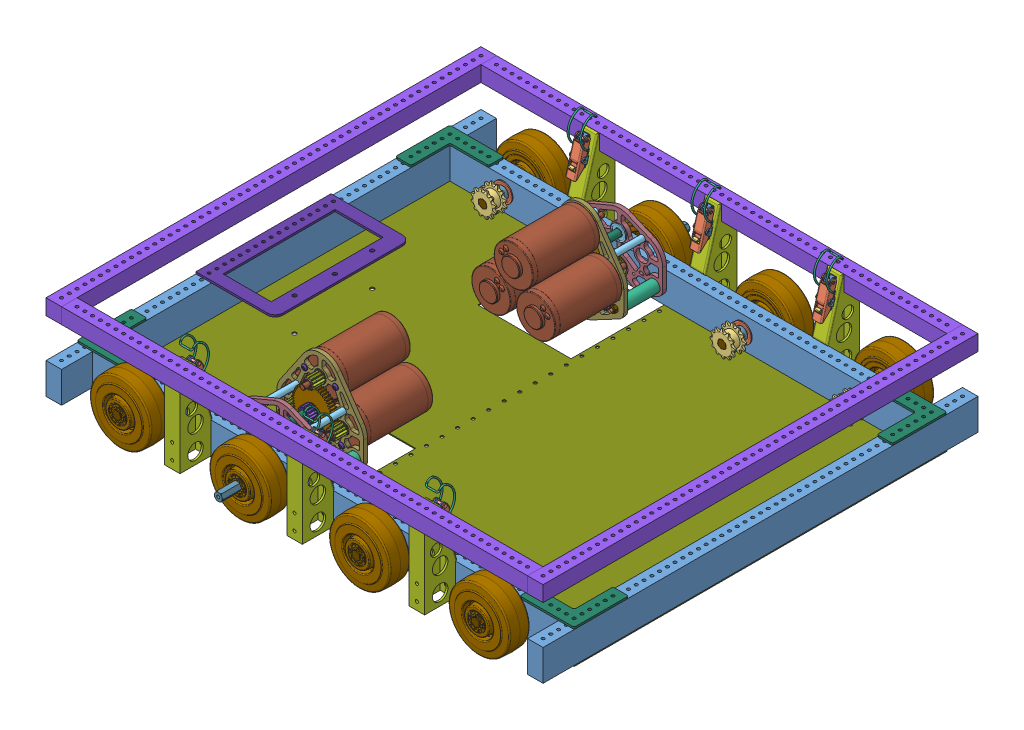
SolidWorks assembly 1991-17-DA-006, configuration Default. Lengths in mm.
Overall size (1080.45 209.9 1407.35).
201 component instances, 45 part files, 16 mates.
Components (placement in the parent):
- 1991-17-DA-001-1: 1991-17-DA-001 [Default] at (549.2577 816.7647 1011.7032) size (1080.45 199.26 1407.35)
  - Master Frame Drivetrain-1: Master Frame Drivetrain [Default] at (262.4677 448.4138 629.0158) size (812.8 50.8 711.2)
  - 1991-17-DP-005-1: 1991-17-DP-005 [Default] at (-30.8765 451.5888 927.4658) x (-0.365997 0.930616 0) z (0.930616 0.365997 0) size (31.12 7.94 31.12)
  - 1991-17-DP-005-2: 1991-17-DP-005 [Default] at (164.6777 448.4138 927.4658) x (1 0 0) z (0 -1 0) size (31.12 7.94 31.12)
  - 1991-17-DP-005-3: 1991-17-DP-005 [Default] at (555.8119 451.5888 927.4658) x (0.865913 0.500195 0) z (0.500195 -0.865913 0) size (31.12 7.94 31.12)
  - 1991-17-DP-005-4: 1991-17-DP-005 [Default] at (360.2577 448.4138 927.4658) x (0.906341 -0.422547 0) z (-0.422547 -0.906341 0) size (31.12 7.94 31.12)
  - 1991-17-DP-005-5: 1991-17-DP-005 [Default] at (-30.8765 451.5888 914.7658) x (1 0 0) z (0 1 0) size (31.12 7.94 31.12)
  - 1991-17-DP-005-7: 1991-17-DP-005 [Default] at (360.2577 448.4138 914.7658) x (1 0 0) z (0 1 0) size (31.12 7.94 31.12)
  - 1991-17-DP-005-8: 1991-17-DP-005 [Default] at (555.8119 451.5888 914.7658) x (1 0 0) z (0 1 0) size (31.12 7.94 31.12)
  - 1991-17-DP-005-9: 1991-17-DP-005 [Default] at (555.8119 451.5888 343.2658) x (1 0 0) z (0 -1 0) size (31.12 7.94 31.12)
  - 1991-17-DP-005-10: 1991-17-DP-005 [Default] at (555.8119 451.5888 330.5658) x (1 0 0) z (0 1 0) size (31.12 7.94 31.12)
  - 1991-17-DP-005-11: 1991-17-DP-005 [Default] at (360.2577 448.4138 330.5658) x (1 0 0) z (0 1 0) size (31.12 7.94 31.12)
  - 1991-17-DP-005-12: 1991-17-DP-005 [Default] at (360.2577 448.4138 343.2658) x (1 0 0) z (0 -1 0) size (31.12 7.94 31.12)
  - 1991-17-DP-005-13: 1991-17-DP-005 [Default] at (164.6777 448.4138 343.2658) x (1 0 0) z (0 -1 0) size (31.12 7.94 31.12)
  - 1991-17-DP-005-15: 1991-17-DP-005 [Default] at (-30.8765 451.5888 330.5658) x (1 0 0) z (0 1 0) size (31.12 7.94 31.12)
  - 1991-17-DP-005-16: 1991-17-DP-005 [Default] at (-30.8765 451.5888 343.2658) x (1 0 0) z (0 -1 0) size (31.12 7.94 31.12)
  - 1991-17-DP-006-1: 1991-17-DP-006 [Default] at (-30.8765 451.5888 876.45) x (0.66365 -0.748043 0) z (0 0 1) size (40.29 40.29 21.35)
  - 1991-17-DP-006-2: 1991-17-DP-006 [Default] at (360.2577 448.4138 876.45) size (40.29 40.29 21.35)
  - 1991-17-DP-006-3: 1991-17-DP-006 [Default] at (555.8119 451.5888 876.45) size (40.29 40.29 21.35)
  - 1991-17-DP-006-4: 1991-17-DP-006 [Default] at (555.8119 451.5888 364.5255) x (0.485442 0.874269 0) z (0 0 1) size (40.29 40.29 21.35)
  - 1991-17-DP-006-5: 1991-17-DP-006 [Default] at (360.2577 448.4138 364.5255) x (0.316887 -0.948463 0) z (0 0 1) size (40.29 40.29 21.35)
  - 1991-17-DP-006-6: 1991-17-DP-006 [Default] at (-30.8765 451.5888 364.5255) size (40.29 40.29 21.35)
  - 1991-17-DA-002-1: 1991-17-DA-002 [Default] at (164.6777 495.4546 838.5658) size (142.06 172.49 287.64)
    - 217-2731-1: 217-2731 [Default] at (0 -47.0408 0) x (0.751182 -0.660095 0) z (-0.660095 -0.751182 0) size (31.12 7.94 31.12)
    - 217-2733-1: 217-2733 [Default] at (0 0 7.9375) x (0 0 -1) z (0.979051 -0.203616 0) size (7.11 24.61 24.61)
    - 217-2733-2: 217-2733 [Default] at (0 0 61.9125) x (0 0 1) z (-0.773016 -0.634387 0) size (7.11 24.61 24.61)
    - 217-2734-1: 217-2734 [Default] at (0 -47.0408 90.4875) x (1 0 0) z (0 -1 0) size (31.12 7.94 31.12)
    - 217-3099-001_12t-1: 217-3099-001_12t [Default] at (-36.6388 -14.5464 15.811) x (0.998588 0.053124 0) z (0 0 1) size (18.01 18.01 19.05)
    - 217-3099-001_12t-2: 217-3099-001_12t [Default] at (36.6388 -14.5464 15.811) x (0.998588 -0.053124 0) z (0 0 1) size (18.01 18.01 19.05)
    - 217-3099-001_12t-3: 217-3099-001_12t [Default] at (-0.0318 39.4208 15.811) x (-0.050001 -0.998749 0) z (0 0 1) size (18.01 18.01 19.05)
    - 217-3100-001_14t-1: 217-3100-001_14t [Default] at (0 0 26.9367) x (0.913978 0.405765 0) z (0 0 1) size (20.32 20.6 12.7)
    - 217-2711-002 Rev1_50t-1: 217-2711-002 Rev1_50t [Default] at (0 0 14.2621) x (-0.21459 -0.976704 0) z (0 0 1) size (66.7 66.76 12.65)
    - 217-2714-002 Rev1_60t-1: 217-2714-002 Rev1_60t [Default] at (0 -47.0408 26.9621) x (0.920953 -0.389675 0) z (0 0 1) size (78.95 78.95 12.65)
    - 217-2000-1: 217-2000 [Default] at (-36.6388 -14.5464 0) x (0 0 -1) z (0.998588 0.053124 0) size (150.2 64.01 64.01)
    - 217-2000-2: 217-2000 [Default] at (-0.0318 39.4208 0) x (0 0 -1) z (-0.050001 -0.998749 0) size (150.2 64.01 64.01)
    - 217-2000-3: 217-2000 [Default] at (36.6388 -14.5464 0) x (0 0 -1) z (0.998588 -0.053124 0) size (150.2 64.01 64.01)
    - 217-3421-001 Rev1-1: 217-3421-001 Rev1 [Default] at origin size (142.02 161.39 6.35)
    - 217-3421-002 Rev1-1: 217-3421-002 Rev1 [Default] at (0 0 69.85) x (-1 0 0) z (0 0 -1) size (142.06 121.97 6.35)
    - 217-3421-004 Rev1-1: 217-3421-004 Rev1 [Default] at (0 -47.0408 90.4875) x (-0.41446 0.910068 0) z (0 0 1) size (15.59 12.7 175.64)
    - 217-3422-001 Rev1-1: 217-3422-001 Rev1 [Default] at (0 0 34.925) x (0.99441 -0.105586 0) z (0 0 1) size (11.11 11.11 68.26)
    - 217-3422-004 Rev2-1: 217-3422-004 Rev2 [Default] at (0 -47.0408 96.8375) size (72.39 47.62 34.67)
    - 217-3421-009 Rev1-1: 217-3421-009 Rev1 [Default] at (35.2895 -39.9105 6.35) x (0 0 -1) z (-0.521716 -0.853119 0) size (15.78 9.26 9.25)
    - 217-3421-009 Rev1-2: 217-3421-009 Rev1 [Default] at (-25.4 40.6908 6.35) x (0 0 -1) z (-0.521716 -0.853119 0) size (15.78 9.26 9.25)
    - 217-3421-009 Rev1-3: 217-3421-009 Rev1 [Default] at (25.3365 38.1508 6.35) x (0 0 -1) z (-0.521716 -0.853119 0) size (15.78 9.26 9.25)
    - 217-3421-009 Rev1-4: 217-3421-009 Rev1 [Default] at (-35.2895 -39.9105 6.35) x (0 0 -1) z (-0.521716 -0.853119 0) size (15.78 9.26 9.25)
    - 217-3421-010 Rev1-1: 217-3421-010 Rev1 [Default] at (57.15 -47.0408 0) x (0.608161 -0.793814 0) z (0.793814 0.608161 0) size (9.53 6.13 11)
    - 217-3421-010 Rev1-2: 217-3421-010 Rev1 [Default] at (-57.15 -47.0408 0) x (0.608161 -0.793814 0) z (0.793814 0.608161 0) size (9.53 6.13 11)
    - 217-3421-011 Rev2_97633A200-1: 217-3421-011 Rev2_97633A200 [Default] at (0 -47.0408 -0.4445) x (0 0 -1) z (0.969555 0.244872 0) size (0.89 16.1 14.34)
    - 217-3422-005 Rev1-1: 217-3422-005 Rev1 [Default] at (57.15 -47.0408 73.025) x (0 0 -1) z (-0.704441 0.709763 0) size (87.6 7.92 7.92)
    - 217-3422-005 Rev1-2: 217-3422-005 Rev1 [Default] at (-57.15 -47.0408 73.025) x (0 0 -1) z (-0.704441 0.709763 0) size (87.6 7.92 7.92)
    - 217-3422-006 Rev1-1: 217-3422-006 Rev1 [Default] at (38.0118 10.8086 69.85) x (0 0 -1) z (-0.961271 0.275605 0) size (81.25 7.92 7.92)
    - 217-3422-006 Rev1-2: 217-3422-006 Rev1 [Default] at (-38.0118 10.8086 69.85) x (0 0 -1) z (-0.961271 0.275605 0) size (81.25 7.92 7.92)
    - 217-3422-007 Rev1-1: 217-3422-007 Rev1 [Default] at (23.8125 -47.0408 95.1993) x (0 0 1) z (-0.890461 -0.455059 0) size (35.11 10.21 10.21)
    - 217-3422-007 Rev1-2: 217-3422-007 Rev1 [Default] at (-23.8125 -47.0408 95.1993) x (0 0 1) z (-0.870387 -0.492369 0) size (35.11 10.21 10.21)
    - 217-3422-002 Rev1-1: 217-3422-002 Rev1 [Default] at (-37.9881 10.8177 34.925) size (9.53 9.53 57.15)
    - 217-3422-002 Rev1-2: 217-3422-002 Rev1 [Default] at (37.9881 10.8177 34.925) size (9.53 9.53 57.15)
    - 217-3422-003 Rev1-1: 217-3422-003 Rev1 [Default] at (-57.15 -47.0408 34.925) size (19.13 19.13 63.5)
    - 217-3422-003 Rev1-2: 217-3422-003 Rev1 [Default] at (57.15 -47.0408 34.925) x (0.853162 0.521647 0) z (0 0 1) size (19.13 19.13 63.5)
    - 217-3257-001 Rev1-1: 217-3257-001 Rev1 [Default] at (0 -47.0408 34.779) size (19.5 19.5 1.59)
    - 217-2758-001 Rev1-1: 217-2758-001 Rev1 [Default] at (0 -47.0408 55.4991) x (-0.35758 0.933882 0) z (0 0 1) size (19.05 19.05 3.17)
    - 217-3259-001 Rev1-1: 217-3259-001 Rev1 [Default] at (0 -47.0408 60.2616) x (-0.351317 0.936256 0) z (0 0 1) size (19.5 19.5 6.35)
    - 217-3261-001 Rev1-1: 217-3261-001 Rev1 [Default] at (0 -47.0408 14.2875) size (19.5 19.5 12.7)
    - 217-3263-001 Rev1-1: 217-3263-001 Rev1 [Default] at (0 -47.0408 77.7875) x (0.762918 -0.646495 0) z (0 0 1) size (19.5 19.5 25.4)
    - 217-2761-001 rev1-1: 217-2761-001 rev1 [Default] at (3.7635 39.2308 16.1) x (0.050001 0.998749 0) z (0 0 1) size (2 2 20)
    - 217-2761-001 rev1-2: 217-2761-001 rev1 [Default] at (-36.8407 -10.7518 16.1) x (0.998588 0.053124 0) z (0 0 1) size (2 2 20)
    - 217-2761-001 rev1-3: 217-2761-001 rev1 [Default] at (36.8407 -10.7518 16.1) x (0.998588 -0.053124 0) z (0 0 1) size (2 2 20)
    - 217-2614-002_98430A132-1: 217-2614-002_98430A132 [Default] at (-0.0318 39.4208 6.286) x (0 0 -1) z (0.996945 0.078111 0) size (1.2 14.83 14.83)
    - 217-2614-002_98430A132-2: 217-2614-002_98430A132 [Default] at (36.6388 -14.5464 6.286) x (0 0 -1) z (0.996945 0.078111 0) size (1.2 14.83 14.83)
    - 217-2614-002_98430A132-3: 217-2614-002_98430A132 [Default] at (-36.6388 -14.5464 6.286) x (0 0 -1) z (0.996945 0.078111 0) size (1.2 14.83 14.83)
    - 217-2614-002_98430A132-4: 217-2614-002_98430A132 [Default] at (-36.6388 -14.5464 26.4028) x (0 0 -1) z (0.996945 0.078111 0) size (1.2 14.83 14.83)
    - 217-2614-002_98430A132-5: 217-2614-002_98430A132 [Default] at (36.6388 -14.5464 26.4028) x (0 0 -1) z (0.996945 0.078111 0) size (1.2 14.83 14.83)
    - 217-2614-002_98430A132-6: 217-2614-002_98430A132 [Default] at (-0.0318 39.4208 26.4028) x (0 0 -1) z (0.996945 0.078111 0) size (1.2 14.83 14.83)
    - 217-3257-001 Rev1-2: 217-3257-001 Rev1 [Default] at (0 -47.0408 64.2938) size (19.5 19.5 1.59)
  - 1991-17-DA-002-2: 1991-17-DA-002 [Default] at (164.6777 495.4546 419.4658) x (-1 0 0) z (0 0 -1) size (142.06 172.49 287.64)
    - 217-2731-1: 217-2731 [Default] at (0 -47.0408 0) x (0.751182 -0.660095 0) z (-0.660095 -0.751182 0) size (31.12 7.94 31.12)
    - 217-2733-1: 217-2733 [Default] at (0 0 7.9375) x (0 0 -1) z (0.979051 -0.203616 0) size (7.11 24.61 24.61)
    - 217-2733-2: 217-2733 [Default] at (0 0 61.9125) x (0 0 1) z (-0.773016 -0.634387 0) size (7.11 24.61 24.61)
    - 217-2734-1: 217-2734 [Default] at (0 -47.0408 90.4875) x (1 0 0) z (0 -1 0) size (31.12 7.94 31.12)
    - 217-3099-001_12t-1: 217-3099-001_12t [Default] at (-36.6388 -14.5464 15.811) x (0.998588 0.053124 0) z (0 0 1) size (18.01 18.01 19.05)
    - 217-3099-001_12t-2: 217-3099-001_12t [Default] at (36.6388 -14.5464 15.811) x (0.998588 -0.053124 0) z (0 0 1) size (18.01 18.01 19.05)
    - 217-3099-001_12t-3: 217-3099-001_12t [Default] at (-0.0318 39.4208 15.811) x (-0.050001 -0.998749 0) z (0 0 1) size (18.01 18.01 19.05)
    - 217-3100-001_14t-1: 217-3100-001_14t [Default] at (0 0 26.9367) x (0.913978 0.405765 0) z (0 0 1) size (20.32 20.6 12.7)
    - 217-2711-002 Rev1_50t-1: 217-2711-002 Rev1_50t [Default] at (0 0 14.2621) x (-0.21459 -0.976704 0) z (0 0 1) size (66.7 66.76 12.65)
    - 217-2714-002 Rev1_60t-1: 217-2714-002 Rev1_60t [Default] at (0 -47.0408 26.9621) x (0.920953 -0.389675 0) z (0 0 1) size (78.95 78.95 12.65)
    - 217-2000-1: 217-2000 [Default] at (-36.6388 -14.5464 0) x (0 0 -1) z (0.998588 0.053124 0) size (150.2 64.01 64.01)
    - 217-2000-2: 217-2000 [Default] at (-0.0318 39.4208 0) x (0 0 -1) z (-0.050001 -0.998749 0) size (150.2 64.01 64.01)
    - 217-2000-3: 217-2000 [Default] at (36.6388 -14.5464 0) x (0 0 -1) z (0.998588 -0.053124 0) size (150.2 64.01 64.01)
    - 217-3421-001 Rev1-1: 217-3421-001 Rev1 [Default] at origin size (142.02 161.39 6.35)
    - 217-3421-002 Rev1-1: 217-3421-002 Rev1 [Default] at (0 0 69.85) x (-1 0 0) z (0 0 -1) size (142.06 121.97 6.35)
    - 217-3421-004 Rev1-1: 217-3421-004 Rev1 [Default] at (0 -47.0408 90.4875) x (-0.41446 0.910068 0) z (0 0 1) size (15.59 12.7 175.64)
    - 217-3422-001 Rev1-1: 217-3422-001 Rev1 [Default] at (0 0 34.925) x (0.99441 -0.105586 0) z (0 0 1) size (11.11 11.11 68.26)
    - 217-3422-004 Rev2-1: 217-3422-004 Rev2 [Default] at (0 -47.0408 96.8375) size (72.39 47.62 34.67)
    - 217-3421-009 Rev1-1: 217-3421-009 Rev1 [Default] at (35.2895 -39.9105 6.35) x (0 0 -1) z (-0.521716 -0.853119 0) size (15.78 9.26 9.25)
    - 217-3421-009 Rev1-2: 217-3421-009 Rev1 [Default] at (-25.4 40.6908 6.35) x (0 0 -1) z (-0.521716 -0.853119 0) size (15.78 9.26 9.25)
    - 217-3421-009 Rev1-3: 217-3421-009 Rev1 [Default] at (25.3365 38.1508 6.35) x (0 0 -1) z (-0.521716 -0.853119 0) size (15.78 9.26 9.25)
    - 217-3421-009 Rev1-4: 217-3421-009 Rev1 [Default] at (-35.2895 -39.9105 6.35) x (0 0 -1) z (-0.521716 -0.853119 0) size (15.78 9.26 9.25)
    - 217-3421-010 Rev1-1: 217-3421-010 Rev1 [Default] at (57.15 -47.0408 0) x (0.608161 -0.793814 0) z (0.793814 0.608161 0) size (9.53 6.13 11)
    - 217-3421-010 Rev1-2: 217-3421-010 Rev1 [Default] at (-57.15 -47.0408 0) x (0.608161 -0.793814 0) z (0.793814 0.608161 0) size (9.53 6.13 11)
    - 217-3421-011 Rev2_97633A200-1: 217-3421-011 Rev2_97633A200 [Default] at (0 -47.0408 -0.4445) x (0 0 -1) z (0.969555 0.244872 0) size (0.89 16.1 14.34)
    - 217-3422-005 Rev1-1: 217-3422-005 Rev1 [Default] at (57.15 -47.0408 73.025) x (0 0 -1) z (-0.704441 0.709763 0) size (87.6 7.92 7.92)
    - 217-3422-005 Rev1-2: 217-3422-005 Rev1 [Default] at (-57.15 -47.0408 73.025) x (0 0 -1) z (-0.704441 0.709763 0) size (87.6 7.92 7.92)
    - 217-3422-006 Rev1-1: 217-3422-006 Rev1 [Default] at (38.0118 10.8086 69.85) x (0 0 -1) z (-0.961271 0.275605 0) size (81.25 7.92 7.92)
    - 217-3422-006 Rev1-2: 217-3422-006 Rev1 [Default] at (-38.0118 10.8086 69.85) x (0 0 -1) z (-0.961271 0.275605 0) size (81.25 7.92 7.92)
    - 217-3422-007 Rev1-1: 217-3422-007 Rev1 [Default] at (23.8125 -47.0408 95.1993) x (0 0 1) z (-0.890461 -0.455059 0) size (35.11 10.21 10.21)
    - 217-3422-007 Rev1-2: 217-3422-007 Rev1 [Default] at (-23.8125 -47.0408 95.1993) x (0 0 1) z (-0.870387 -0.492369 0) size (35.11 10.21 10.21)
    - 217-3422-002 Rev1-1: 217-3422-002 Rev1 [Default] at (-37.9881 10.8177 34.925) size (9.53 9.53 57.15)
    - 217-3422-002 Rev1-2: 217-3422-002 Rev1 [Default] at (37.9881 10.8177 34.925) size (9.53 9.53 57.15)
    - 217-3422-003 Rev1-1: 217-3422-003 Rev1 [Default] at (-57.15 -47.0408 34.925) size (19.13 19.13 63.5)
    - 217-3422-003 Rev1-2: 217-3422-003 Rev1 [Default] at (57.15 -47.0408 34.925) x (0.853162 0.521647 0) z (0 0 1) size (19.13 19.13 63.5)
    - 217-3257-001 Rev1-1: 217-3257-001 Rev1 [Default] at (0 -47.0408 34.779) size (19.5 19.5 1.59)
    - 217-2758-001 Rev1-1: 217-2758-001 Rev1 [Default] at (0 -47.0408 55.4991) x (-0.35758 0.933882 0) z (0 0 1) size (19.05 19.05 3.17)
    - 217-3259-001 Rev1-1: 217-3259-001 Rev1 [Default] at (0 -47.0408 60.2616) x (-0.351317 0.936256 0) z (0 0 1) size (19.5 19.5 6.35)
    - 217-3261-001 Rev1-1: 217-3261-001 Rev1 [Default] at (0 -47.0408 14.2875) size (19.5 19.5 12.7)
    - 217-3263-001 Rev1-1: 217-3263-001 Rev1 [Default] at (0 -47.0408 77.7875) x (0.762918 -0.646495 0) z (0 0 1) size (19.5 19.5 25.4)
    - 217-2761-001 rev1-1: 217-2761-001 rev1 [Default] at (3.7635 39.2308 16.1) x (0.050001 0.998749 0) z (0 0 1) size (2 2 20)
    - 217-2761-001 rev1-2: 217-2761-001 rev1 [Default] at (-36.8407 -10.7518 16.1) x (0.998588 0.053124 0) z (0 0 1) size (2 2 20)
    - 217-2761-001 rev1-3: 217-2761-001 rev1 [Default] at (36.8407 -10.7518 16.1) x (0.998588 -0.053124 0) z (0 0 1) size (2 2 20)
    - 217-2614-002_98430A132-1: 217-2614-002_98430A132 [Default] at (-0.0318 39.4208 6.286) x (0 0 -1) z (0.996945 0.078111 0) size (1.2 14.83 14.83)
    - 217-2614-002_98430A132-2: 217-2614-002_98430A132 [Default] at (36.6388 -14.5464 6.286) x (0 0 -1) z (0.996945 0.078111 0) size (1.2 14.83 14.83)
    - 217-2614-002_98430A132-3: 217-2614-002_98430A132 [Default] at (-36.6388 -14.5464 6.286) x (0 0 -1) z (0.996945 0.078111 0) size (1.2 14.83 14.83)
    - 217-2614-002_98430A132-4: 217-2614-002_98430A132 [Default] at (-36.6388 -14.5464 26.4028) x (0 0 -1) z (0.996945 0.078111 0) size (1.2 14.83 14.83)
    - 217-2614-002_98430A132-5: 217-2614-002_98430A132 [Default] at (36.6388 -14.5464 26.4028) x (0 0 -1) z (0.996945 0.078111 0) size (1.2 14.83 14.83)
    - 217-2614-002_98430A132-6: 217-2614-002_98430A132 [Default] at (-0.0318 39.4208 26.4028) x (0 0 -1) z (0.996945 0.078111 0) size (1.2 14.83 14.83)
    - 217-3257-001 Rev1-2: 217-3257-001 Rev1 [Default] at (0 -47.0408 64.2938) size (19.5 19.5 1.59)
  - 1991-17-DP-006-7: 1991-17-DP-006 [Default] at (164.6777 448.4138 876.45) size (40.29 40.29 21.35)
  - 1991-17-DP-006-8: 1991-17-DP-006 [Default] at (164.6777 448.4138 364.5255) size (40.29 40.29 21.35)
  - 1991-17-DP-007-1: 1991-17-DP-007 [Default] at (360.2577 448.4138 351.2032) x (0.999949 -0.01009 0) z (0 0 1) size (19.05 19.05 11.18)
  - 1991-17-DP-007-2: 1991-17-DP-007 [Default] at (555.8119 451.5888 351.2033) x (0.991459 -0.130416 0) z (0 0 1) size (19.05 19.05 11.18)
  - 1991-17-DP-007-3: 1991-17-DP-007 [Default] at (555.8119 451.5888 895.6523) x (0.999479 -0.032269 0) z (0 0 1) size (19.05 19.05 11.18)
  - 1991-17-DP-007-4: 1991-17-DP-007 [Default] at (360.2577 448.4138 895.6523) x (0.999398 0.034699 0) z (0 0 1) size (19.05 19.05 11.18)
  - 1991-17-DP-007-5: 1991-17-DP-007 [Default] at (-30.8765 451.5888 895.6524) x (0.918059 -0.396445 0) z (0 0 1) size (19.05 19.05 11.18)
  - 1991-17-DP-007-6: 1991-17-DP-007 [Default] at (-30.8765 451.5888 351.2032) size (19.05 19.05 11.18)
  - 1991-17-DP-009-1: 1991-17-DP-009 [Default] at (668.8677 473.8138 844.9158) x (-1 0 0) z (0 0 -1) size (88.9 3.17 88.9)
  - 1991-17-DP-009-2: 1991-17-DP-009 [Default] at (579.9677 473.8138 324.2158) x (0 0 1) z (-1 0 0) size (88.9 3.17 88.9)
  - 1991-17-DP-009-3: 1991-17-DP-009 [Default] at (-143.9323 473.8138 413.1158) size (88.9 3.17 88.9)
  - 1991-17-DP-009-4: 1991-17-DP-009 [Default] at (-55.0323 473.8138 933.8158) x (0 0 -1) z (1 0 0) size (88.9 3.17 88.9)
  - 1991-17-DP-010-1: 1991-17-DP-010 [Default] at (-143.9323 421.4263 324.2158) x (0 0 1) z (-1 0 0) size (609.6 1.59 812.8)
  - 1991-17-DP-011-1: 1991-17-DP-011 [Default] at (-79.1623 473.8138 629.0158) x (0 0 1) z (-1 0 0) size (220.98 3.17 129.54)
  - 1991-17-DP-012-1: 1991-17-DP-012 [Default] at (-30.8807 451.5996 329.7529) x (-0.365997 0.930616 0) z (0 0 1) size (14.66 12.7 107.95)
  - 1991-17-DP-012-2: 1991-17-DP-012 [Default] at (360.2672 448.4205 329.7529) x (0.087234 -0.996188 0) z (0 0 1) size (14.66 12.7 107.95)
  - 1991-17-DP-012-3: 1991-17-DP-012 [Default] at (555.8019 451.5946 329.7529) x (0.865913 0.500195 0) z (0 0 1) size (14.66 12.7 107.95)
  - 1991-17-DP-012-4: 1991-17-DP-012 [Default] at (555.8019 451.5946 928.2787) x (0.865913 0.500195 0) z (0 0 1) size (14.66 12.7 107.95)
  - 1991-17-DP-012-5: 1991-17-DP-012 [Default] at (360.2672 448.4205 928.2787) x (0.087234 -0.996188 0) z (0 0 1) size (14.66 12.7 107.95)
  - 1991-17-DP-012-6: 1991-17-DP-012 [Default] at (-30.8807 451.5996 928.2787) x (-0.365997 0.930616 0) z (0 0 1) size (14.66 12.7 107.95)
  - 1991-17-DA-003-1: 1991-17-DA-003 [Default] at (462.8327 537.6125 948.7419) x (1 0 0) z (0 0.961524 0.274721) size (23.75 31.36 88.93)
    - 1256B-1: 1256B [Default] at origin size (21.85 11.11 42.86)
    - 1256A-1: 1256A [Default] at (0 7.786 -8.5531) size (16.4 11.75 57.3)
    - 1256E-1: 1256E [Default] at (0 2.1 5.2687) size (17.5 15.13 27.5)
    - 569-2-1: 569-2 [Default] at (0.2 7.62 16.6687) size (18.02 5.86 5.81)
    - RIVET-2-1: RIVET-2 [Default] at (0 0 -8.2313) size (4.23 2.64 4.27)
    - 645C-1: 645C [Default] at (0 6.3871 15.3627) x (-1 0 0) z (0 -0.098785 -0.995109) size (23.75 26.55 49.93)
  - 1991-17-DA-003-2: 1991-17-DA-003 [Default] at (262.8077 537.6125 948.7419) x (1 0 0) z (0 0.961524 0.274721) size (23.75 31.36 88.93)
    - 1256B-1: 1256B [Default] at origin size (21.85 11.11 42.86)
    - 1256A-1: 1256A [Default] at (0 7.786 -8.5531) size (16.4 11.75 57.3)
    - 1256E-1: 1256E [Default] at (0 2.1 5.2687) size (17.5 15.13 27.5)
    - 569-2-1: 569-2 [Default] at (0.2 7.62 16.6687) size (18.02 5.86 5.81)
    - RIVET-2-1: RIVET-2 [Default] at (0 0 -8.2313) size (4.23 2.64 4.27)
    - 645C-1: 645C [Default] at (0 6.3871 15.3627) x (-1 0 0) z (0 -0.098785 -0.995109) size (23.75 26.55 49.93)
  - 1991-17-DA-003-3: 1991-17-DA-003 [Default] at (60.2427 537.6125 948.7419) x (1 0 0) z (0 0.961524 0.274721) size (23.75 31.36 88.93)
    - 1256B-1: 1256B [Default] at origin size (21.85 11.11 42.86)
    - 1256A-1: 1256A [Default] at (0 7.786 -8.5531) size (16.4 11.75 57.3)
    - 1256E-1: 1256E [Default] at (0 2.1 5.2687) size (17.5 15.13 27.5)
    - 569-2-1: 569-2 [Default] at (0.2 7.62 16.6687) size (18.02 5.86 5.81)
    - RIVET-2-1: RIVET-2 [Default] at (0 0 -8.2313) size (4.23 2.64 4.27)
    - 645C-1: 645C [Default] at (0 6.3871 15.3627) x (-1 0 0) z (0 -0.098785 -0.995109) size (23.75 26.55 49.93)
  - 1991-17-DA-003-4: 1991-17-DA-003 [Default] at (462.8327 536.9449 309.2975) x (-1 0 0) z (0 0.961524 -0.274721) size (23.75 31.36 88.93)
    - 1256B-1: 1256B [Default] at origin size (21.85 11.11 42.86)
    - 1256A-1: 1256A [Default] at (0 7.786 -8.5531) size (16.4 11.75 57.3)
    - 1256E-1: 1256E [Default] at (0 2.1 5.2687) size (17.5 15.13 27.5)
    - 569-2-1: 569-2 [Default] at (0.2 7.62 16.6687) size (18.02 5.86 5.81)
    - RIVET-2-1: RIVET-2 [Default] at (0 0 -8.2313) size (4.23 2.64 4.27)
    - 645C-1: 645C [Default] at (0 6.3871 15.3627) x (-1 0 0) z (0 -0.098785 -0.995109) size (23.75 26.55 49.93)
  - 1991-17-DA-003-5: 1991-17-DA-003 [Default] at (262.8077 536.9932 309.4665) x (-1 0 0) z (0 0.961524 -0.274721) size (23.75 31.36 88.93)
    - 1256B-1: 1256B [Default] at origin size (21.85 11.11 42.86)
    - 1256A-1: 1256A [Default] at (0 7.786 -8.5531) size (16.4 11.75 57.3)
    - 1256E-1: 1256E [Default] at (0 2.1 5.2687) size (17.5 15.13 27.5)
    - 569-2-1: 569-2 [Default] at (0.2 7.62 16.6687) size (18.02 5.86 5.81)
    - RIVET-2-1: RIVET-2 [Default] at (0 0 -8.2313) size (4.23 2.64 4.27)
    - 645C-1: 645C [Default] at (0 6.3871 15.3627) x (-1 0 0) z (0 -0.098785 -0.995109) size (23.75 26.55 49.93)
  - 1991-17-DA-003-6: 1991-17-DA-003 [Default] at (60.2427 536.9932 309.4665) x (-1 0 0) z (0 0.961524 -0.274721) size (23.75 31.36 88.93)
    - 1256B-1: 1256B [Default] at origin size (21.85 11.11 42.86)
    - 1256A-1: 1256A [Default] at (0 7.786 -8.5531) size (16.4 11.75 57.3)
    - 1256E-1: 1256E [Default] at (0 2.1 5.2687) size (17.5 15.13 27.5)
    - 569-2-1: 569-2 [Default] at (0.2 7.62 16.6687) size (18.02 5.86 5.81)
    - RIVET-2-1: RIVET-2 [Default] at (0 0 -8.2313) size (4.23 2.64 4.27)
    - 645C-1: 645C [Default] at (0 6.3871 15.3627) x (-1 0 0) z (0 -0.098785 -0.995109) size (23.75 26.55 49.93)
  - 1991-17-DP-019-1: 1991-17-DP-019 [Default] at (462.4927 423.0138 298.8158) x (0 0 1) z (-1 0 0) size (53.25 139.97 25.4)
  - 1991-17-DP-019-2: 1991-17-DP-019 [Default] at (262.4677 423.0138 298.8158) x (0 0 1) z (-1 0 0) size (53.25 139.97 25.4)
  - 1991-17-DP-019-3: 1991-17-DP-019 [Default] at (62.4427 423.0138 298.8158) x (0 0 1) z (-1 0 0) size (53.25 139.97 25.4)
  - 1991-17-DP-019-4: 1991-17-DP-019 [Default] at (462.4927 423.0138 959.2158) x (0 0 -1) z (1 0 0) size (53.25 139.97 25.4)
  - 1991-17-DP-019-5: 1991-17-DP-019 [Default] at (262.4677 423.0138 959.2158) x (0 0 -1) z (1 0 0) size (53.25 139.97 25.4)
  - 1991-17-DP-019-6: 1991-17-DP-019 [Default] at (62.4427 423.0138 959.2158) x (0 0 -1) z (1 0 0) size (53.25 139.97 25.4)
  - 1991-17-DP-014-2: 1991-17-DP-014 [Default] at (-118.5323 550.0138 273.4158) x (0 0 1) z (-1 0 0) size (711.2 25.4 812.8)
- 1991-17-DP-008-1: 1991-17-DP-008 [Default] at (518.3812 1268.3536 1971.427) x (0 0 -1) z (0.999988 0.004986 0) size (42.89 101.6 101.6)
- 1991-17-DP-008-2: 1991-17-DP-008 [Default] at (713.9354 1265.1786 1971.427) x (0 0 -1) z (1 0 0) size (42.89 101.6 101.6)
- 1991-17-DP-008-3: 1991-17-DP-008 [Default] at (909.5154 1265.1786 1971.427) x (0 0 -1) z (1 0 0) size (42.89 101.6 101.6)
- 1991-17-DP-008-4: 1991-17-DP-008 [Default] at (1105.0697 1268.3536 1971.427) x (0 0 -1) z (1 0 0) size (42.89 101.6 101.6)
- 1991-17-DP-008-5: 1991-17-DP-008 [Default] at (1105.0697 1268.3536 1310.011) x (0 0 1) z (0.27605 0.961143 0) size (42.89 101.6 101.6)
- 1991-17-DP-008-6: 1991-17-DP-008 [Default] at (909.5154 1265.1786 1310.011) x (0 0 1) z (0.964745 0.263186 0) size (42.89 101.6 101.6)
- 1991-17-DP-008-7: 1991-17-DP-008 [Default] at (713.9354 1265.1786 1310.011) x (0 0 1) z (-1 0 0) size (42.89 101.6 101.6)
- 1991-17-DP-008-8: 1991-17-DP-008 [Default] at (518.3812 1268.3536 1310.011) x (0 0 1) z (-1 0 0) size (42.89 101.6 101.6)
Mates (geometry in assembly coordinates):
- Concentric1: concentric anti-aligned: cylinder of 1991-17-DA-001-1/1991-17-DP-005-15 through (518.3812 1268.3536 1342.269) axis (0 0 -1) radius 15.5575; cone of 1991-17-DP-008-8 through (518.3812 1268.3536 1318.5141) axis (0 0 1)
- Concentric2: concentric anti-aligned: cylinder of 1991-17-DA-001-1/1991-17-DA-002-2/217-2734-1 through (713.9354 1265.1786 1340.6815) axis (0 0 -1) radius 9.525; cone of 1991-17-DP-008-7 through (713.9354 1265.1786 1318.5141) axis (0 0 1)
- Concentric3: concentric anti-aligned: cylinder of 1991-17-DA-001-1/1991-17-DP-005-11 through (909.5154 1265.1786 1342.269) axis (0 0 -1) radius 15.5575; cone of 1991-17-DP-008-6 through (909.5154 1265.1786 1318.5141) axis (0 0 1)
- Concentric4: concentric anti-aligned: cylinder of 1991-17-DA-001-1/1991-17-DP-005-10 through (1105.0697 1268.3536 1342.269) axis (0 0 -1) radius 15.5575; cone of 1991-17-DP-008-5 through (1105.0697 1268.3536 1318.5141) axis (0 0 1)
- Coincident1: coincident aligned: plane of 1991-17-DP-008-5 through (1105.0697 1268.3536 1288.8655) normal (0 0 -1); plane of 1991-17-DP-008-6 through (909.5154 1265.1786 1288.8655) normal (0 0 -1)
- Coincident2: coincident aligned: plane of 1991-17-DP-008-6 through (909.5154 1265.1786 1288.8655) normal (0 0 -1); plane of 1991-17-DP-008-7 through (713.9354 1265.1786 1288.8655) normal (0 0 -1)
- Coincident3: coincident aligned: plane of 1991-17-DP-008-7 through (713.9354 1265.1786 1288.8655) normal (0 0 -1); plane of 1991-17-DP-008-8 through (518.3812 1268.3536 1288.8655) normal (0 0 -1)
- Distance1: distance = 3.175 mm anti-aligned: plane of 1991-17-DP-008-8 through (518.3812 1268.3536 1331.1565) normal (0 0 1); plane of 1991-17-DA-001-1/1991-17-DP-005-15 through (524.7312 1268.3536 1334.3315) normal (0 0 -1)
- Concentric5: concentric aligned: cylinder of 1991-17-DA-001-1/1991-17-DP-006-1 through (518.3812 1268.3536 1903.063) axis (0 0 -1) radius 12.7; cone of 1991-17-DP-008-1 through (518.3812 1268.3536 1962.9238) axis (0 0 -1)
- Concentric6: concentric aligned: cylinder of 1991-17-DA-001-1/1991-17-DP-006-7 through (713.9354 1265.1786 1903.063) axis (0 0 -1) radius 12.7; cone of 1991-17-DP-008-2 through (713.9354 1265.1786 1962.9238) axis (0 0 -1)
- Concentric7: concentric aligned: cylinder of 1991-17-DA-001-1/1991-17-DP-006-2 through (909.5154 1265.1786 1903.063) axis (0 0 -1) radius 12.7; cone of 1991-17-DP-008-3 through (909.5154 1265.1786 1962.9238) axis (0 0 -1)
- Concentric8: concentric aligned: cylinder of 1991-17-DA-001-1/1991-17-DP-006-3 through (1105.0697 1268.3536 1903.063) axis (0 0 -1) radius 12.7; cone of 1991-17-DP-008-4 through (1105.0697 1268.3536 1962.9238) axis (0 0 -1)
- Coincident5: coincident aligned: plane of 1991-17-DP-008-3 through (909.5154 1265.1786 1992.5725) normal (0 0 1); plane of 1991-17-DP-008-4 through (1105.0697 1268.3536 1992.5725) normal (0 0 1)
- Coincident6: coincident aligned: plane of 1991-17-DP-008-2 through (713.9354 1265.1786 1992.5725) normal (0 0 1); plane of 1991-17-DP-008-3 through (909.5154 1265.1786 1992.5725) normal (0 0 1)
- Coincident7: coincident aligned: plane of 1991-17-DP-008-1 through (518.3812 1268.3536 1992.5725) normal (0 0 1); plane of 1991-17-DP-008-2 through (713.9354 1265.1786 1992.5725) normal (0 0 1)
- Distance2: distance = 3.175 mm anti-aligned: plane of 1991-17-DA-001-1/1991-17-DP-005-1 through (516.0571 1274.263 1947.1065) normal (0 0 1); plane of 1991-17-DP-008-1 through (518.3812 1268.3536 1950.2815) normal (0 0 -1)
